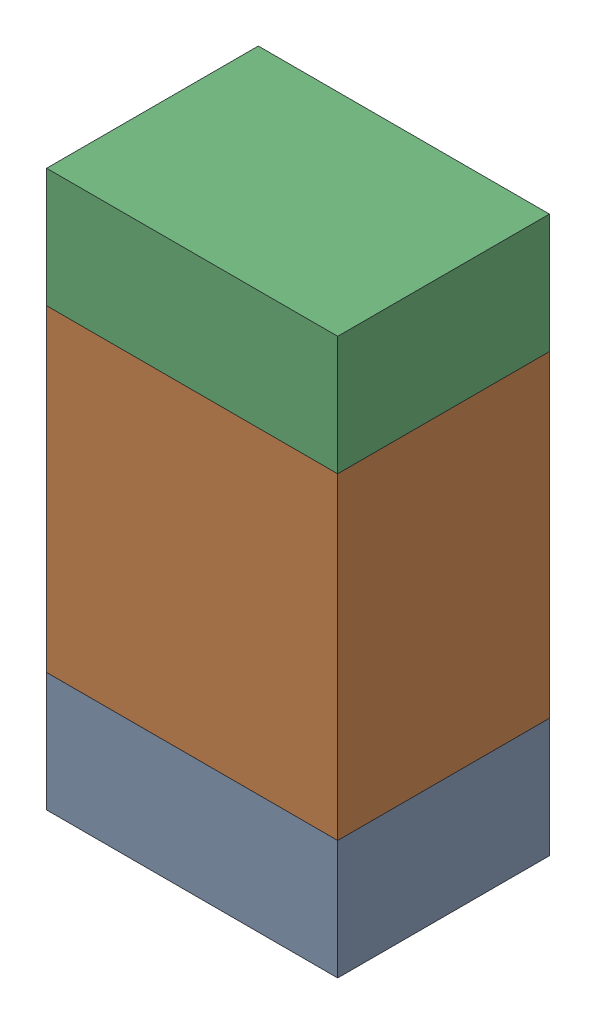
SolidWorks assembly R314_1PCB, configuration Default. Lengths in mm.
Overall size (0.55 1.05 0.4).
6 component instances, 2 part files, 0 mates.
Components (placement in the parent):
- 846483288-1: 846483288 [Default] at (133.4001 112.6874 -2.0638) size (0.55 0.22 0.4)
  - Extruded_12-1: Extruded_12 [Default] at origin size (0.55 0.22 0.4)
- 846483424-1: 846483424 [Default] at (133.4001 113.0999 -2.0638) size (0.55 0.6 0.4)
  - Extruded_13-1: Extruded_13 [Default] at origin size (0.55 0.6 0.4)
- 846483288-2: 846483288 [Default] at (133.4001 113.5124 -2.0638) size (0.55 0.22 0.4)
  - Extruded_12-1: Extruded_12 [Default] at origin size (0.55 0.22 0.4)
